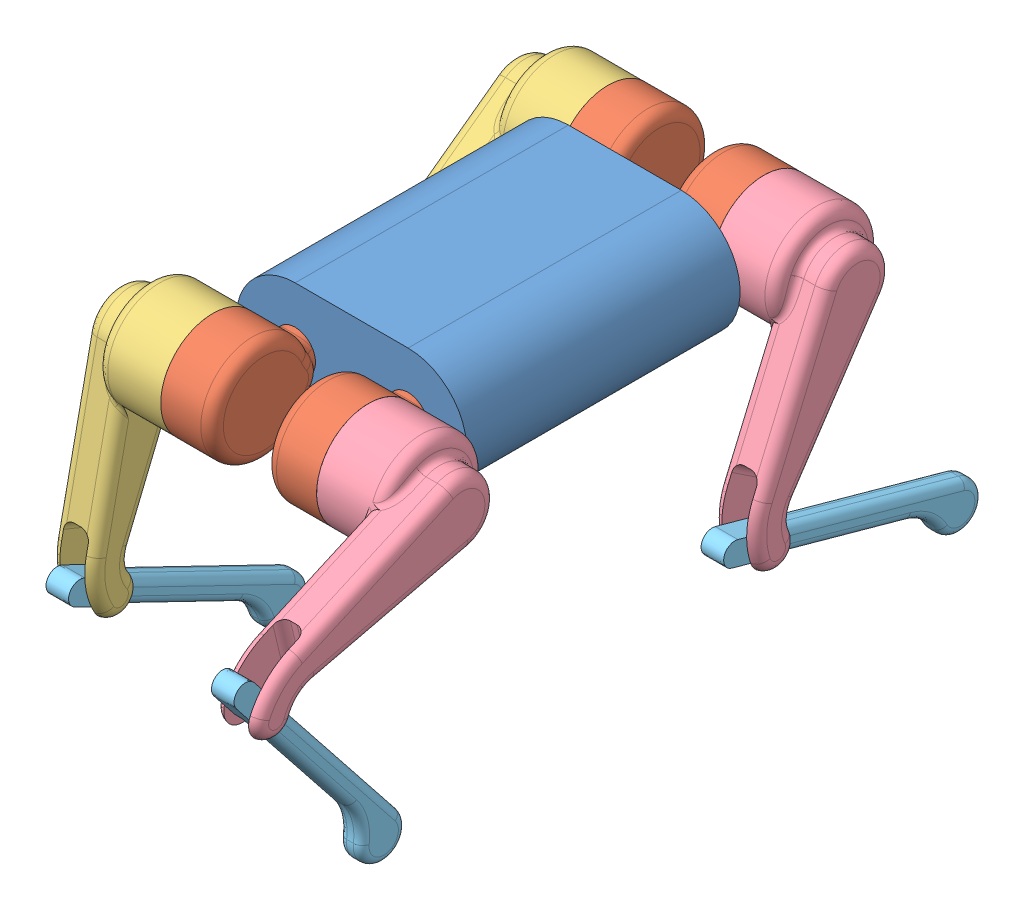
SolidWorks assembly 简要装配, configuration 默认. Lengths in mm.
Overall size (305.13 355.07 679.07).
13 component instances, 5 part files, 26 mates.
Components (placement in the parent):
- 身体草图-1: 身体草图 [默认] at (1.0557 13.0648 121) size (204 104 242)
- 髋关节草图-1: 髋关节草图 [默认] at (51.0557 13.0648 417) x (-1 0 0) z (0 0 -1) size (45.5 92 101.38)
- 髋关节草图-2: 髋关节草图 [默认] at (-48.9443 13.0648 417) x (1 0 0) z (0 0 -1) size (45.5 92 101.38)
- 髋关节草图-3: 髋关节草图 [默认] at (51.0557 13.0648 67) x (-1 0 0) z (0 0 1) size (45.5 92 101.38)
- 髋关节草图-4: 髋关节草图 [默认] at (-48.9443 13.0648 67) size (45.5 92 101.38)
- 大腿草图-1: 大腿草图 [默认] at (-112.9443 13.0648 67) x (0 0.807541 0.589811) z (-1 0 0) size (92 242.8 83.56)
- 大腿草图-2: 大腿草图 [默认] at (-112.9443 13.0648 417) x (0 0.203651 0.979044) z (-1 0 0) size (92 242.8 83.56)
- 大腿草图-右-1: 大腿草图-右 [默认] at (115.0557 13.0648 417) x (0 0.913701 0.406387) z (-1 0 0) size (92 242.8 83.56)
- 大腿草图-右-2: 大腿草图-右 [默认] at (115.0557 13.0648 67) x (0 0.392683 0.919674) z (-1 0 0) size (92 242.8 83.56)
- 小腿草图-1: 小腿草图 [默认] at (144.0557 -60.0849 581.4662) x (0 -0.577247 0.816569) z (-1 0 0) size (40 239.95 22)
- 小腿草图-2: 小腿草图 [默认] at (-121.9443 -93.1012 212.3574) x (0 -0.777091 0.629389) z (-1 0 0) size (40 239.95 22)
- 小腿草图-3: 小腿草图 [默认] at (144.0557 -152.4765 137.683) x (0 -0.947506 0.319739) z (-1 0 0) size (40 239.95 22)
- 小腿草图-4: 小腿草图 [默认] at (-121.9443 -163.163 453.6572) x (0 -0.874307 0.485373) z (-1 0 0) size (40 239.95 22)
Mates (geometry in assembly coordinates):
- 重合1: coincident anti-aligned: plane of 身体草图-1 through (-48.9443 13.0648 363) normal (0 0 1); plane of 髋关节草图-1 through (51.0557 13.0648 363) normal (0 0 -1)
- 同心1: concentric anti-aligned: circle of 身体草图-1; circle of 髋关节草图-1
- 重合2: coincident anti-aligned: plane of 身体草图-1 through (-48.9443 13.0648 363) normal (0 0 1); plane of 髋关节草图-2 through (-48.9443 13.0648 363) normal (0 0 -1)
- 同心2: concentric anti-aligned: circle of 身体草图-1; circle of 髋关节草图-2
- 重合3: coincident anti-aligned: plane of 身体草图-1 through (-48.9443 13.0648 121) normal (0 0 -1); plane of 髋关节草图-3 through (51.0557 13.0648 121) normal (0 0 1)
- 同心3: concentric aligned: circle of 身体草图-1; circle of 髋关节草图-3
- 重合4: coincident anti-aligned: plane of 身体草图-1 through (-48.9443 13.0648 121) normal (0 0 -1); plane of 髋关节草图-4 through (-48.9443 13.0648 121) normal (0 0 1)
- 同心4: concentric aligned: circle of 身体草图-1; circle of 髋关节草图-4
- 同心5: concentric aligned: circle of 髋关节草图-2; circle of 大腿草图-2
- 距离1: distance = 1 mm anti-aligned: plane of 小腿草图-1 through (124.0557 -207.0674 477.5616) normal (-1 0 0); plane of 大腿草图-右-1 through (123.0557 -68.233 542.0761) normal (1 0 0)
- 同心6: concentric aligned: circle of 大腿草图-右-1; circle of 小腿草图-1
- 距离2: distance = 1 mm anti-aligned: plane of 小腿草图-4 through (-121.9443 -250.5302 296.2819) normal (1 0 0); plane of 大腿草图-2 through (-120.9443 -135.9445 424.0409) normal (-1 0 0)
- 同心7: concentric anti-aligned: circle of 大腿草图-2; circle of 小腿草图-4
- 同心8: concentric aligned: circle of 大腿草图-右-2; circle of 小腿草图-3
- 距离3: distance = 1 mm anti-aligned: plane of 小腿草图-3 through (124.0557 -210.0294 -32.8681) normal (-1 0 0); plane of 大腿草图-右-2 through (123.0557 -131.6314 103.2816) normal (1 0 0)
- 距离4: distance = 1 mm anti-aligned: plane of 小腿草图-2 through (-121.9443 -206.3911 72.4811) normal (1 0 0); plane of 大腿草图-1 through (-120.9443 -92.7654 172.1348) normal (-1 0 0)
- 同心9: concentric anti-aligned: circle of 大腿草图-1; circle of 小腿草图-2
- 重合10: coincident anti-aligned: plane of 髋关节草图-4 through (-67.9443 13.0648 67) normal (-1 0 0); plane of 大腿草图-1 through (-67.9443 13.0648 67) normal (1 0 0)
- 重合11: coincident aligned: circle of 髋关节草图-4; circle of 大腿草图-1
- 重合12: coincident anti-aligned: plane of 髋关节草图-2 through (-67.9443 13.0648 417) normal (-1 0 0); plane of 大腿草图-2 through (-67.9443 13.0648 417) normal (1 0 0)
- 重合13: coincident aligned: circle of 髋关节草图-3; circle of 大腿草图-右-2
- 重合14: coincident aligned: circle of 髋关节草图-1; circle of 大腿草图-右-1
- 平行1: parallel aligned: plane of 髋关节草图-1 through (70.0557 13.0648 417) normal (1 0 0)
- 平行2: parallel anti-aligned: plane of 髋关节草图-2 through (-67.9443 13.0648 417) normal (-1 0 0)
- 平行3: parallel anti-aligned: plane of 髋关节草图-4 through (-67.9443 13.0648 67) normal (-1 0 0)
- 平行4: parallel aligned: plane of 髋关节草图-3 through (70.0557 13.0648 67) normal (1 0 0)
